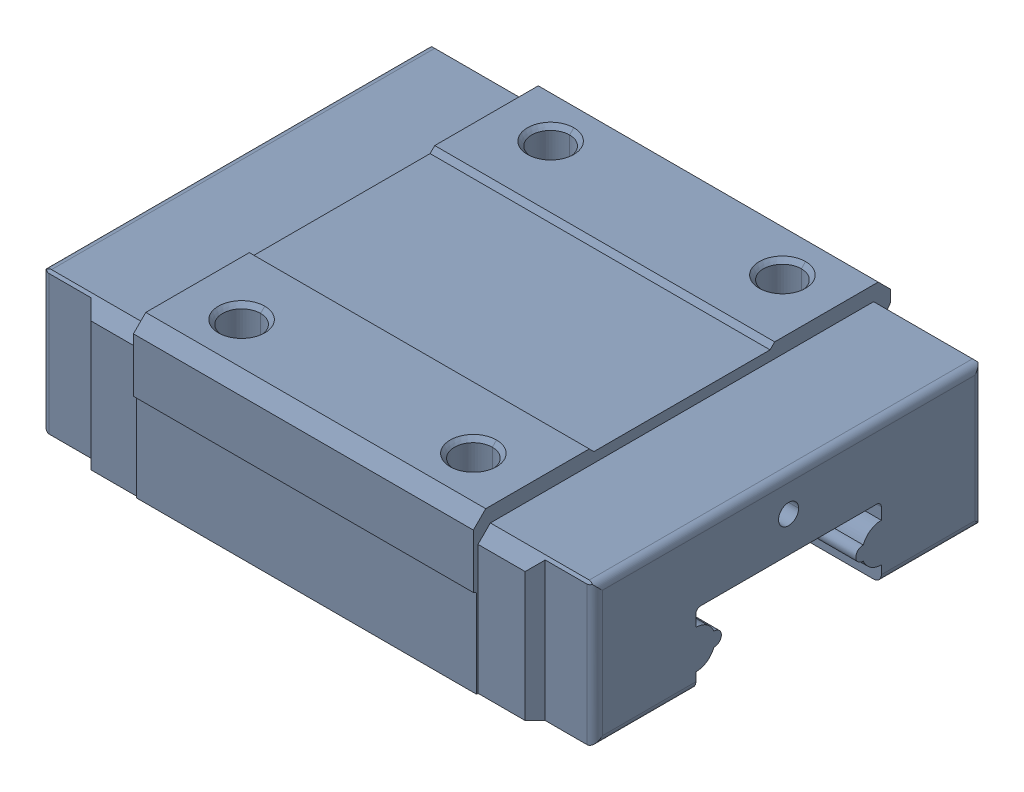
SolidWorks assembly MR_12MN_SS1_V0_N_35_8L_5_5_8__17_9_0_0_0_, configuration Default. Lengths in mm.
Overall size (35.81 10.1 27).
2 component instances, 2 part files, 0 mates.
Components (placement in the parent):
- MR_12MN_SS1_V0_N_35_8L_5_5_8__17_9_0_0_0__3-1: MR_12MN_SS1_V0_N_35_8L_5_5_8__17_9_0_0_0__3 [Default] at (17.9 2.9 0) size (35.81 10.1 27)
- MR_12MN_SS1_V0_N_35_8L_5_5_8__17_9_0_0_0__5-1: MR_12MN_SS1_V0_N_35_8L_5_5_8__17_9_0_0_0__5 [Default] at origin (suppressed, hidden)
